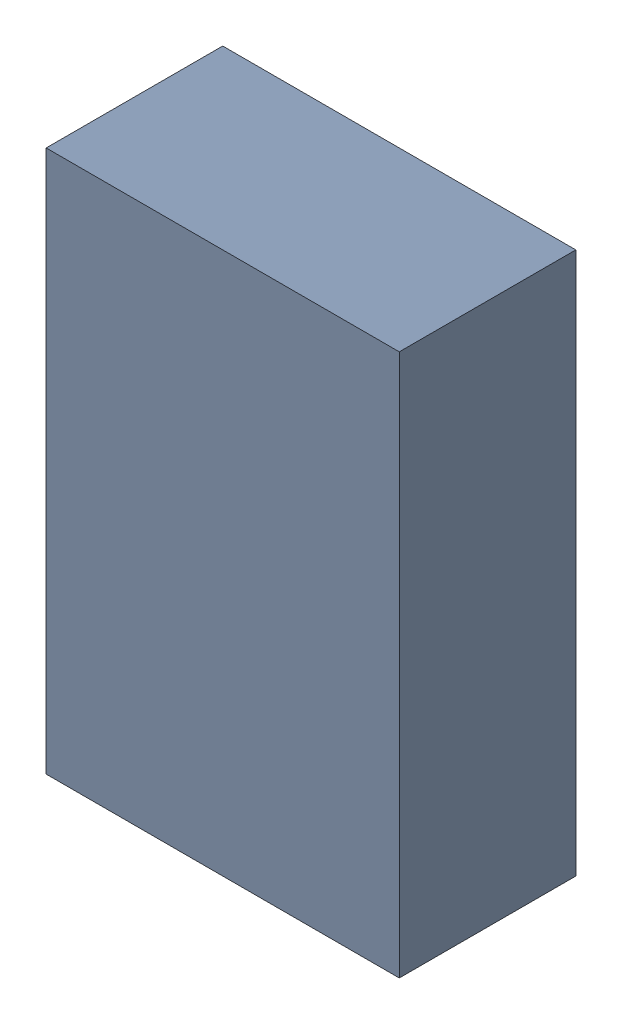
SolidWorks assembly R2-2, configuration Default. Lengths in mm.
Overall size (1.4 2.15 0.7).
2 component instances, 1 part files, 0 mates.
Components (placement in the parent):
- 959208120-2-1: 959208120-2 [Default] at (111.8912 75.852 0) size (1.4 2.15 0.7)
  - Extruded-82-1: Extruded-82 [Default] at origin size (1.4 2.15 0.7)
